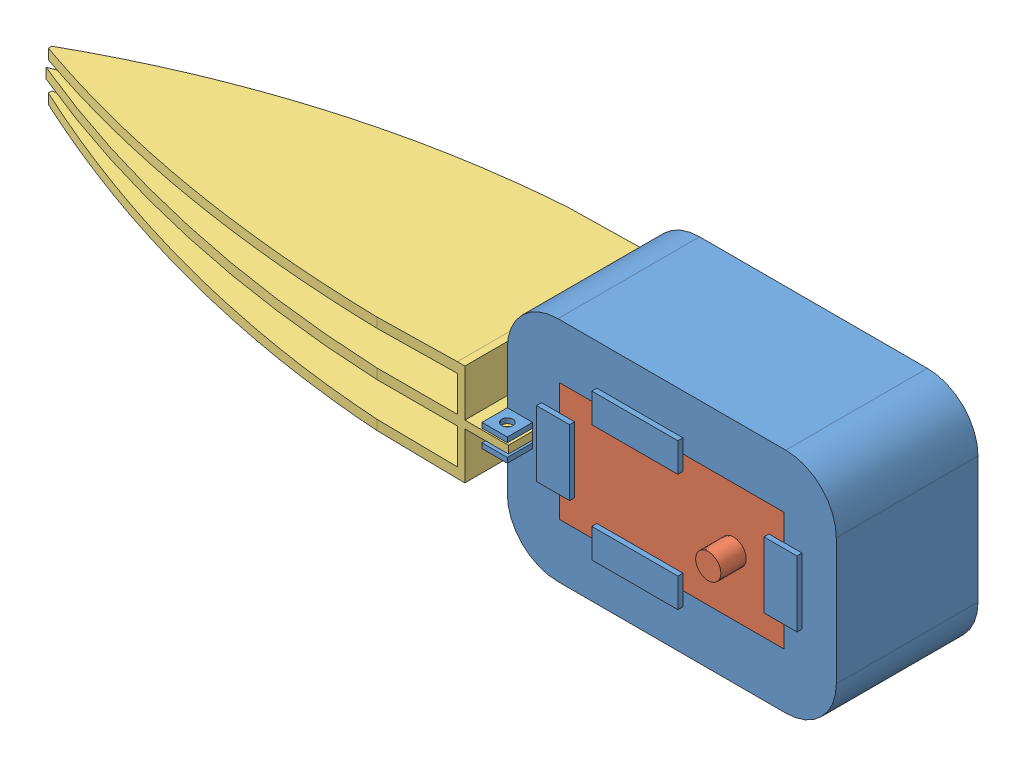
SolidWorks assembly 3fin_tail, configuration 預設. Lengths in mm.
Overall size (170.1 45 38.21).
3 component instances, 3 part files, 7 mates.
Components (placement in the parent):
- bus2_tail-1: bus2_tail [預設] at (14.0556 0.1345 51) size (65 45 38)
- bus_servo-1: bus_servo [預設] at (6.5688 11.6276 79) x (1 0 0) z (0 1 0) size (44.4 38 23.4)
- bus_final_tail-1: bus_final_tail [預設] at (-49.9697 0.1345 64.2694) x (-1 0 0.00071) z (0 1 0) size (110.1 38.13 24.53)
Mates (geometry in assembly coordinates):
- 重合/共線/共點1: coincident anti-aligned: plane of bus2_tail-1 through (-35.579 11.8345 90) normal (0 -1 0); plane of bus_servo-1 through (-35.579 11.8345 51) normal (0 1 0)
- 重合/共線/共點2: coincident anti-aligned: plane of bus2_tail-1 through (-35.579 -11.5655 90) normal (0 1 0); plane of bus_servo-1 through (-35.579 -11.5655 51) normal (0 -1 0)
- 重合/共線/共點3: coincident anti-aligned: plane of bus2_tail-1 through (-35.579 11.8345 90) normal (1 0 0); plane of bus_servo-1 through (-35.579 -11.5655 51) normal (-1 0 0)
- 重合/共線/共點4: coincident aligned: plane of bus2_tail-1 through (14.0556 0.1345 79) normal (0 0 1); plane of bus_servo-1 through (6.5688 11.6276 79) normal (0 0 1)
- 同軸心1: concentric: cylinder of bus2_tail-1 through (-43.379 5.1345 81.5) axis (0 -1 0) radius 1.1; cylinder of bus_final_tail-1 through (-43.379 -0.6155 81.5) axis (0 1 0) radius 1.1
- 同軸心2: concentric: cylinder of bus2_tail-1 through (-43.379 5.1345 48.5) axis (0 -1 0) radius 1.1; cylinder of bus_final_tail-1 through (-43.379 -0.6155 48.5) axis (0 1 0) radius 1.1
- 平行相距1: distance = 0.5 mm anti-aligned: plane of bus_final_tail-1 through (-49.9697 -0.6155 64.2694) normal (0 -1 0); plane of bus2_tail-1 through (14.0556 -1.1155 51) normal (0 1 0)
